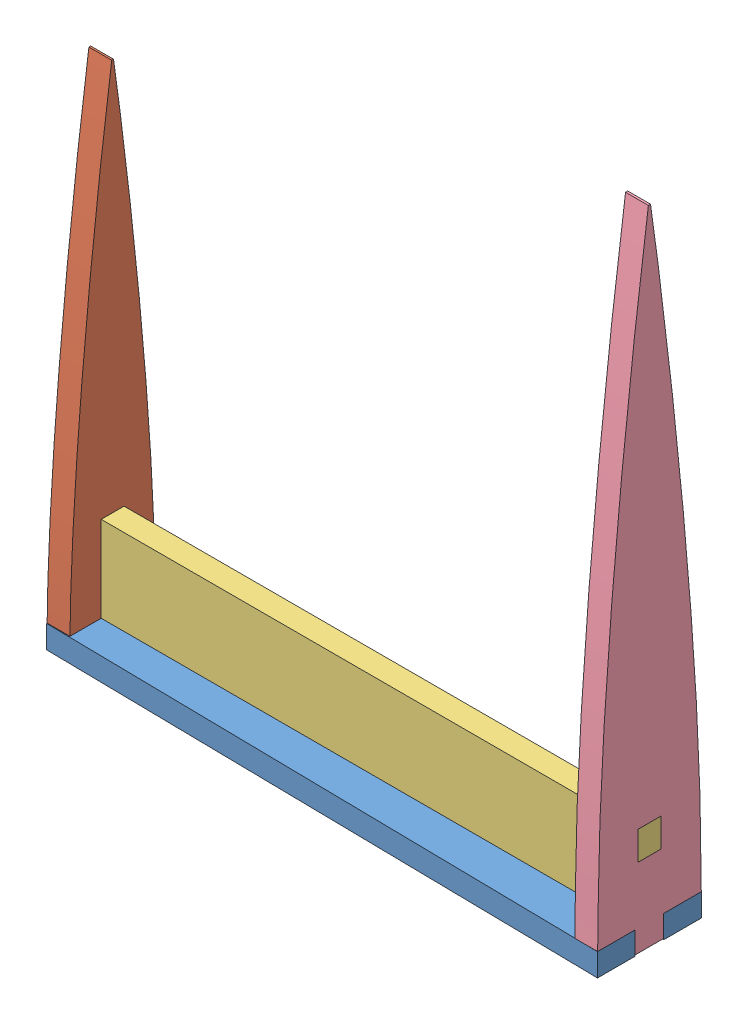
SolidWorks assembly Keel_outline_form, configuration Default. Lengths in mm.
Overall size (124.46 190.56 23.11).
4 component instances, 4 part files, 9 mates.
Components (placement in the parent):
- Keel_outline_face-1: Keel_outline_face [Default] at (-259.2982 -13.1588 120.7295) size (124.46 5.08 23.11)
- Keel_streamline_rib-1: Keel_streamline_rib [Default] at (-259.7434 -60.5298 111.2) x (0 1 0) z (1 0 0) size (158.81 18.96 5.08)
- Keel_streamline_support-1: Keel_streamline_support [Default] at (-254.6634 -8.0788 108.66) x (1 0 0) z (0 -1 0) size (124.46 5.08 23.88)
- Keel_outline_rib-1: Keel_outline_rib [Default] at (-140.3634 -60.5298 111.2) x (0 1 0) z (1 0 0) size (190.56 23.04 5.08)
Mates (geometry in assembly coordinates):
- Coincident1: coincident anti-aligned: plane of Keel_outline_face-1 through (-200.6884 -13.1588 113.74) normal (0 0 -1); plane of Keel_streamline_support-1 through (-254.6634 -8.0788 113.74) normal (0 0 1)
- Coincident2: coincident anti-aligned: plane of Keel_outline_face-1 through (-259.2982 -8.0788 120.7295) normal (0 1 0); plane of Keel_streamline_support-1 through (-254.6634 -8.0788 113.74) normal (0 -1 0)
- Coincident4: coincident anti-aligned: plane of Keel_streamline_rib-1 through (-254.6634 42.793 104.6511) normal (1 0 0); plane of Keel_streamline_support-1 through (-254.6634 -8.0788 113.74) normal (-1 0 0)
- Coincident5: coincident anti-aligned: plane of Keel_streamline_rib-1 through (-254.6634 10.9712 108.66) normal (0 -1 0); plane of Keel_streamline_support-1 through (-254.6634 10.9712 113.74) normal (0 1 0)
- Coincident6: coincident anti-aligned: plane of Keel_streamline_rib-1 through (-254.6634 4.6212 108.66) normal (0 0 1); plane of Keel_streamline_support-1 through (-254.6634 -8.0788 108.66) normal (0 0 -1)
- Coincident10: coincident anti-aligned: plane of Keel_outline_face-1 through (-254.6634 -8.0788 108.025) normal (-1 0 0); plane of Keel_streamline_rib-1 through (-254.6634 42.793 104.6511) normal (1 0 0)
- Coincident11: coincident: plane of Keel_streamline_support-1 through (-140.3634 -8.0788 113.74) normal (1 0 0); plane of Keel_outline_rib-1 through (-140.3634 58.7127 102.9231) normal (-1 0 0)
- Coincident12: coincident: plane of Keel_streamline_support-1 through (-254.6634 -8.0788 108.66) normal (0 0 -1); plane of Keel_outline_rib-1 through (-135.2834 4.6212 108.66) normal (0 0 1)
- Coincident13: coincident anti-aligned: plane of Keel_outline_face-1 through (-259.2982 -8.0788 120.7295) normal (0 1 0); plane of Keel_outline_rib-1 through (-135.2834 -8.0788 99.61) normal (0 -1 0)
